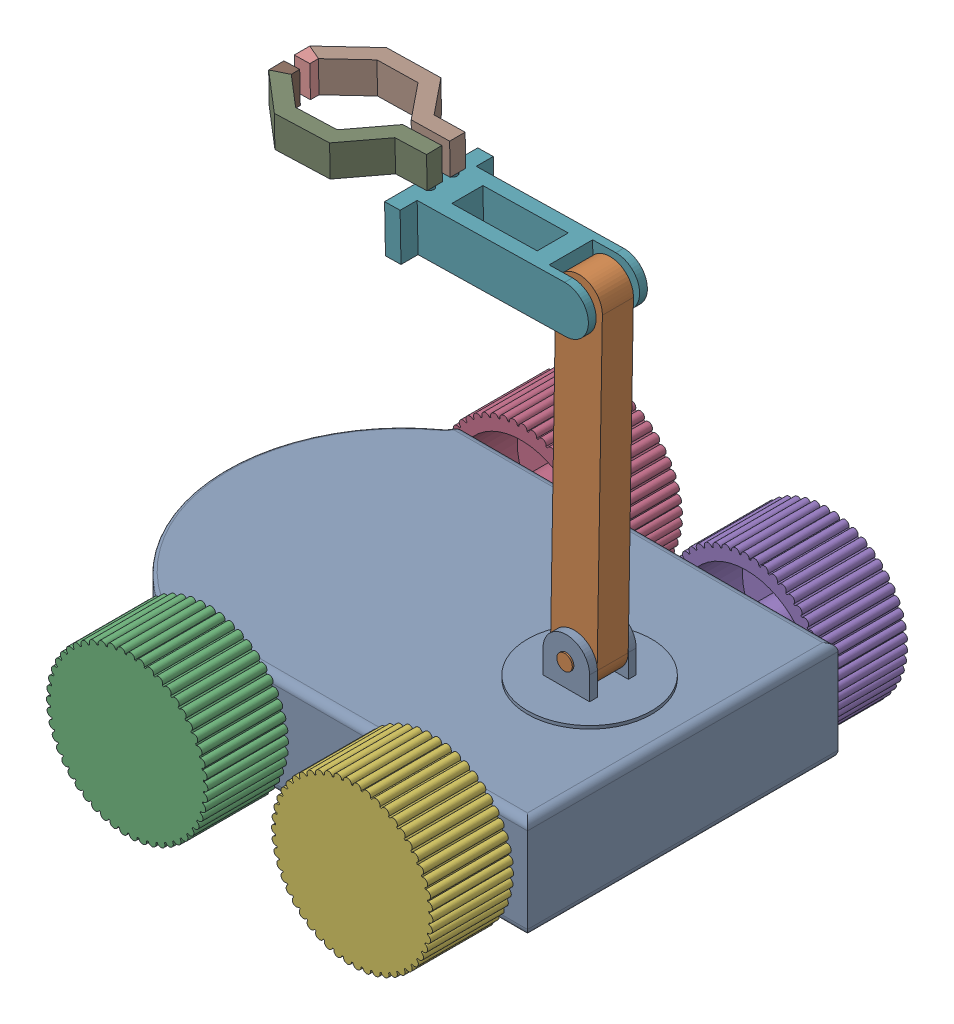
SolidWorks assembly robot, configuration Default. Lengths in mm.
Overall size (296.34 357.3 305.8).
11 component instances, 11 part files, 24 mates.
Components (placement in the parent):
- base-1: base [Default] at (-2.6999 -36.0148 25.8926) size (294.13 97 220)
- shoulder-3: shoulder [Default] at (88.835 145.9711 15.8926) x (0 0 1) z (0.016794 0.999859 0) size (32 30 230)
- wheel_1-1: wheel_1 [Default] at (-57.6999 -3.5148 172.8244) x (0 0 -1) z (0.806669 -0.591004 0) size (52 103.91 103.98)
- wheel_2-2: wheel_2 [Default] at (-57.6999 -3.5148 -121.0391) x (0 0 1) z (-0.983003 -0.183587 0) size (52 103.91 103.98)
- wheel_4-1: wheel_4 [Default] at (87.3001 -3.5148 -121.0391) x (0 0 1) z (-0.975137 -0.221602 0) size (52 103.91 103.98)
- wheel_3-1: wheel_3 [Default] at (87.3001 -3.5148 172.8244) x (0 0 -1) z (0.989404 -0.14519 0) size (52 103.91 103.98)
- elbow-1: elbow [Default] at (8.6542 244.4025 25.8926) x (0.99982 0.018986 0) z (0 0 1) size (120 36 60)
- gripper-1: gripper [Default] at (-53.7925 270.2215 21.0177) x (0.99982 0.018986 -0.000507) z (0.000507 0.00001 1) size (100 20 33.31)
- gripper-2-1: gripper-2 [Default] at (-53.8319 270.2208 31.5777) x (0.999671 0.018984 -0.017241) z (-0.017238 -0.000327 -0.999851) size (100 20 33.31)
- right end-1: right end [Default] at (-53.7925 270.2215 21.0177) x (0.99982 0.018986 -0.000507) z (0.000507 0.00001 1) size (10 20 10)
- left end-2: left end [Default] at (-53.8319 270.2208 31.5777) x (0.999671 0.018984 -0.017241) z (-0.017238 -0.000327 -0.999851) size (10 20 10)
Mates (geometry in assembly coordinates):
- Concentric4: concentric anti-aligned: cylinder of base-1 through (87.1556 45.9852 10.8926) axis (0 0 1) radius 5; cylinder of shoulder-3 through (87.1556 45.9852 41.8926) axis (0 0 -1) radius 5
- Concentric5: concentric aligned: cylinder of base-1 through (87.1556 45.9852 10.8926) axis (0 0 1) radius 5; cylinder of shoulder-3 through (87.1556 45.9852 9.8926) axis (0 0 1) radius 5
- Distance2: distance = 5 mm aligned: plane of shoulder-3 through (90.5145 245.957 35.8926) normal (0 0 1); plane of base-1 through (72.3001 60.9852 40.8926) normal (0 0 1)
- Concentric6: concentric aligned: cylinder of base-1 through (-57.6999 -3.5148 135.8926) axis (0 0 -1) radius 7.5; cylinder of wheel_1-1 through (-57.6999 -3.5148 135.8926) axis (0 0 -1) radius 9.75
- Coincident2: coincident anti-aligned: plane of base-1 through (-57.6999 -3.5148 135.8926) normal (0 0 1); plane of wheel_1-1 through (-57.6999 -3.5148 135.8926) normal (0 0 -1)
- Concentric7: concentric: cylinder of base-1 through (87.3001 -3.5148 135.8926) axis (0 0 -1) radius 7.5; cylinder of wheel_2-1 through (87.3001 -3.5148 346.9563) axis (0 0 -1) radius 7.5
- Coincident3: coincident anti-aligned: plane of base-1 through (87.3001 -3.5148 135.8926) normal (0 0 1); plane of wheel_2-1 through (87.3001 -3.5148 135.8926) normal (0 0 -1)
- Concentric8: concentric aligned: cylinder of base-1 through (-57.6999 -3.5148 -84.1074) axis (0 0 1) radius 7.5; cylinder of wheel_2-2 through (-57.6999 -3.5148 -84.1074) axis (0 0 1) radius 9.75
- Concentric9: concentric aligned: cylinder of base-1 through (87.3001 -3.5148 -84.1074) axis (0 0 1) radius 7.5; cylinder of wheel_4-1 through (87.3001 -3.5148 -84.1074) axis (0 0 1) radius 9.75
- Concentric10: concentric aligned: cylinder of base-1 through (87.3001 -3.5148 135.8926) axis (0 0 -1) radius 7.5; cylinder of wheel_3-1 through (87.3001 -3.5148 135.8926) axis (0 0 -1) radius 9.75
- Coincident4: coincident anti-aligned: plane of base-1 through (87.3001 -3.5148 135.8926) normal (0 0 1); plane of wheel_3-1 through (87.3001 -3.5148 135.8926) normal (0 0 -1)
- Coincident5: coincident anti-aligned: plane of base-1 through (87.3001 -3.5148 -84.1074) normal (0 0 -1); plane of wheel_4-1 through (87.3001 -3.5148 -84.1074) normal (0 0 1)
- Coincident6: coincident anti-aligned: plane of base-1 through (-57.6999 -3.5148 -84.1074) normal (0 0 -1); plane of wheel_2-2 through (-57.6999 -3.5148 -84.1074) normal (0 0 1)
- Concentric11: concentric aligned: cylinder of shoulder-3 through (90.5145 245.957 29.8926) axis (0 0 1) radius 5; cylinder of elbow-1 through (90.5145 245.957 29.8926) axis (0 0 1) radius 5
- Concentric12: concentric aligned: cylinder of shoulder-3 through (90.5145 245.957 21.8926) axis (0 0 -1) radius 5; cylinder of elbow-1 through (90.5145 245.957 21.8926) axis (0 0 -1) radius 5
- Coincident7: coincident anti-aligned: plane of shoulder-3 through (90.5145 245.957 29.8926) normal (0 0 1); plane of elbow-1 through (90.5145 245.957 29.8926) normal (0 0 -1)
- Concentric13: concentric aligned: cylinder of elbow-1 through (-8.0624 265.0888 18.3926) axis (0.018986 -0.99982 0) radius 2.5; cylinder of gripper-1 through (-8.0624 265.0888 18.3926) axis (0.018986 -0.99982 0) radius 2.5
- Coincident8: coincident anti-aligned: plane of elbow-1 through (-8.0624 265.0888 18.3926) normal (-0.018986 0.99982 0); plane of gripper-1 through (-8.0624 265.0888 18.3926) normal (0.018986 -0.99982 0)
- Coincident9: coincident anti-aligned: plane of elbow-1 through (-8.0624 265.0888 33.3926) normal (-0.018986 0.99982 0); plane of gripper-2-1 through (-8.0624 265.0888 33.3926) normal (0.018986 -0.99982 0)
- Concentric14: concentric aligned: cylinder of elbow-1 through (-8.0624 265.0888 33.3926) axis (0.018986 -0.99982 0) radius 2.5; cylinder of gripper-2-1 through (-8.0624 265.0888 33.3926) axis (0.018986 -0.99982 0) radius 2.5
- Coincident14: coincident: moEndPointRef_w of gripper-1; unknown of right end-1
- Coincident15: coincident: unknown of gripper-2-1; unknown of left end-2
- Coincident16: coincident aligned: line of gripper-2-1 through (-105.2481 279.2462 40.0642) axis (0.018986 -0.99982 0); line of left end-2 through (-105.2481 279.2462 40.0642) axis (0.018986 -0.99982 0)
- Coincident17: coincident aligned: line of gripper-1 through (-104.9715 259.2478 13.4419) axis (-0.018986 0.99982 0); line of right end-1 through (-104.9715 259.2478 13.4419) axis (-0.018986 0.99982 0)
